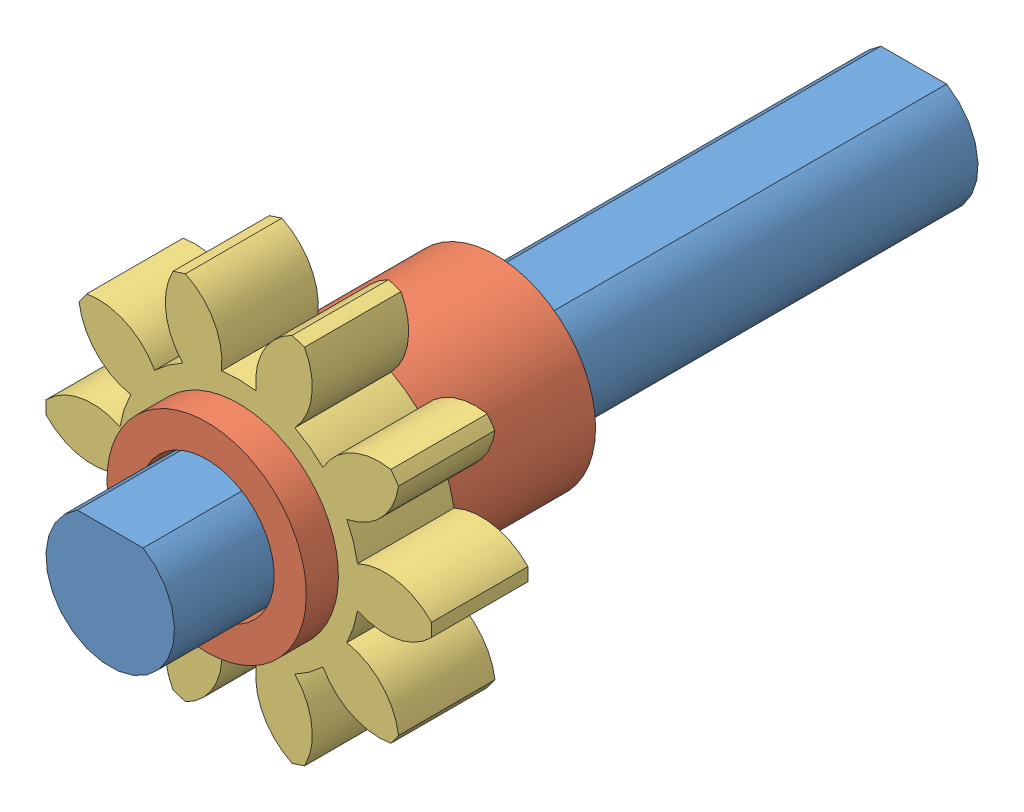
SolidWorks assembly input_shaft, configuration Default. Lengths in mm.
Overall size (12 11.53 25).
4 component instances, 3 part files, 7 mates.
Components (placement in the parent):
- axle-1: axle [25mm] at (9.6586 13.3599 6.3997) size (4 3.72 25)
- spacer-2: spacer [4.2mm ID 5L] at (9.6586 13.3599 19.3997) size (6.2 6.2 5)
- root_gear-1: root_gear [10T 1.0Mod] at (9.6586 13.3599 24.3997) size (12 11.53 3)
- spacer-5: spacer [4.2mm ID 1L] at (9.6586 13.3599 27.3997) x (0.979964 -0.199174 0) z (0 0 1) size (6.2 6.2 1)
Mates (geometry in assembly coordinates):
- Concentric1: concentric aligned: cylinder of axle-1 through (9.6586 13.3599 31.3997) axis (0 0 -1) radius 2; cylinder of spacer-2 through (9.6586 13.3599 24.3997) axis (0 0 -1) radius 2.1
- Concentric3: concentric aligned: cylinder of axle-1 through (9.6586 13.3599 31.3997) axis (0 0 -1) radius 2; cylinder of root_gear-1 through (9.6586 13.3599 27.3997) axis (0 0 -1) radius 2
- Parallel3: parallel anti-aligned: plane of axle-1 through (8.636 15.0787 31.3997) normal (0 1 0); plane of root_gear-1 through (10.9815 14.8599 27.3997) normal (0 -1 0)
- Distance1: distance = 3 mm aligned: plane of spacer-5 through (9.6586 13.3599 28.3997) normal (0 0 1); plane of axle-1 through (9.6586 13.3599 31.3997) normal (0 0 1)
- Concentric5: concentric aligned: cylinder of axle-1 through (9.6586 13.3599 31.3997) axis (0 0 -1) radius 2; cylinder of spacer-5 through (9.6586 13.3599 28.3997) axis (0 0 -1) radius 2.1
- Coincident5: coincident anti-aligned: plane of root_gear-1 through (9.6586 13.3599 27.3997) normal (0 0 1); plane of spacer-5 through (9.6586 13.3599 27.3997) normal (0 0 -1)
- Coincident6: coincident anti-aligned: plane of spacer-2 through (9.6586 13.3599 24.3997) normal (0 0 1); plane of root_gear-1 through (9.6586 13.3599 24.3997) normal (0 0 -1)
